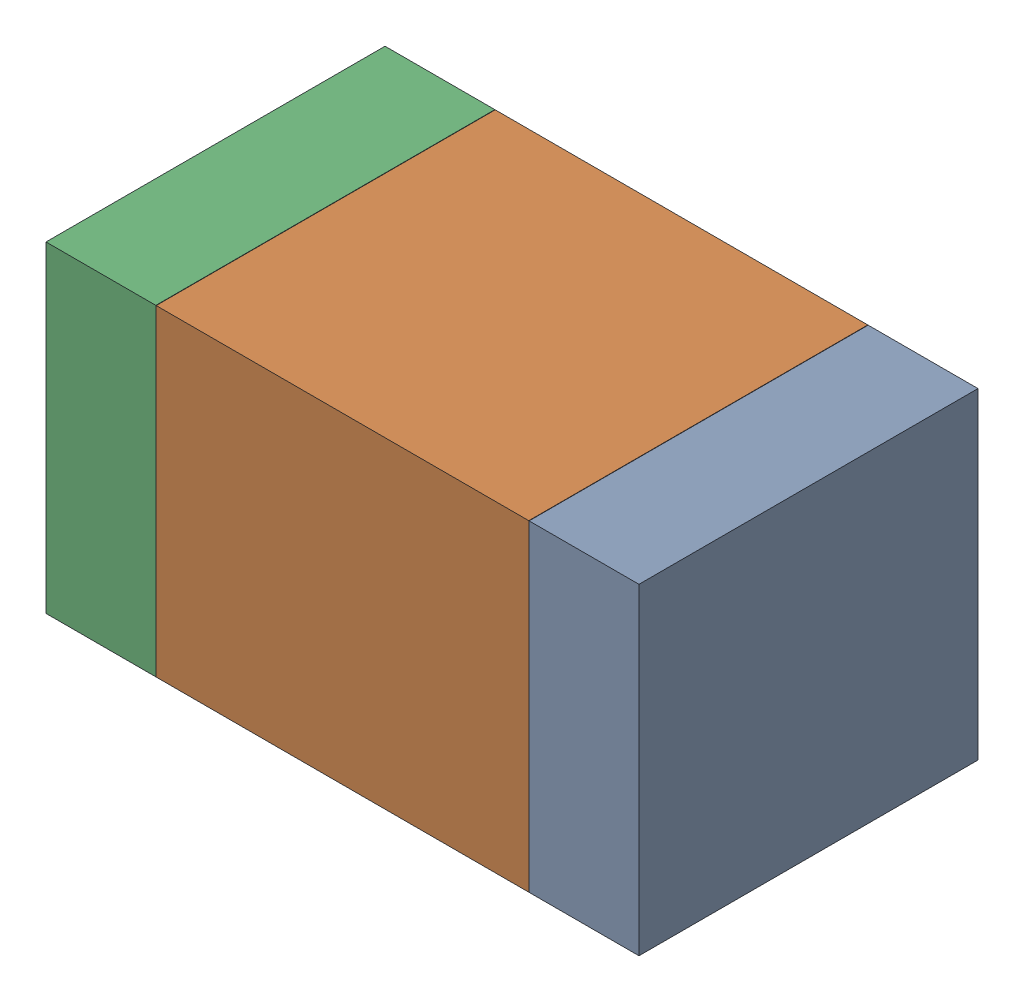
SolidWorks assembly C17, configuration Default. Lengths in mm.
Overall size (1.75 0.95 1).
6 component instances, 2 part files, 0 mates.
Components (placement in the parent):
- 6575498272-1: 6575498272 [Default] at (34.6215 25.908 0) size (0.32 0.95 1)
  - Extruded_8-1: Extruded_8 [Default] at origin size (0.32 0.95 1)
- 6575498112-1: 6575498112 [Default] at (33.909 25.908 0) size (1.1 0.95 1)
  - Extruded_9-1: Extruded_9 [Default] at origin size (1.1 0.95 1)
- 6575498272-2: 6575498272 [Default] at (33.1965 25.908 0) size (0.32 0.95 1)
  - Extruded_8-1: Extruded_8 [Default] at origin size (0.32 0.95 1)
